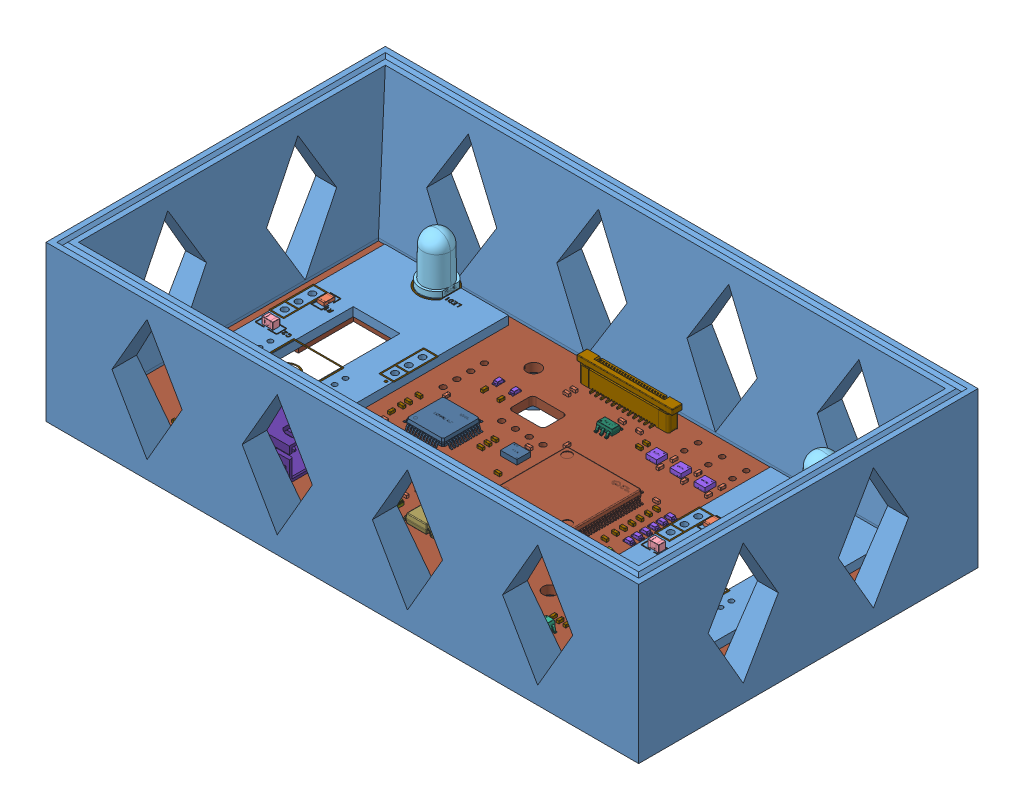
SolidWorks assembly main_v2, configuration Default. Lengths in mm.
Overall size (109.24 29.41 62.54).
295 component instances, 29 part files, 3 mates.
Components (placement in the parent):
- base_v2-1: base_v2 [Default] at origin size (109.24 28.6 62.54)
- 3D_Main_v2_2024-05-05.step-2: 3D_Main_v2_2024-05-05.step [Default] at (0 1.6 0) x (-1 0 0) z (0 1 0) size (99.21 49.97 14.78)
  - SGDi-C2.step-1: SGDi-C2.step [Default] at (-19.05 5.08 1.5862) x (0 -1 0) z (0 0 1) size (1 0.5 0.5)
    - C0402.step-1: C0402.step [Default] at origin size (1 0.5 0.5)
      - SOLID.step-1: SOLID.step [Default] at origin size (1 0.5 0.5)
  - SGDi-C6.step-1: SGDi-C6.step [Default] at (-17.78 -8.89 1.5862) size (1 0.5 0.5)
    - C0402.step-1: C0402.step [Default] at origin size (1 0.5 0.5)
      - SOLID.step-1: SOLID.step [Default] at origin size (1 0.5 0.5)
  - SGDi-C1.step-1: SGDi-C1.step [Default] at (-0.635 -9.525 1.5862) x (0 1 0) z (0 0 1) size (1 0.5 0.5)
    - C0402.step-1: C0402.step [Default] at origin size (1 0.5 0.5)
      - SOLID.step-1: SOLID.step [Default] at origin size (1 0.5 0.5)
  - SGDi-C14.step-1: SGDi-C14.step [Default] at (9.525 4.445 1.5862) size (1 0.5 0.5)
    - C0402.step-1: C0402.step [Default] at origin size (1 0.5 0.5)
      - SOLID.step-1: SOLID.step [Default] at origin size (1 0.5 0.5)
  - SGDi-C12.step-1: SGDi-C12.step [Default] at (20.32 3.175 1.5862) x (-1 0 0) z (0 0 1) size (1 0.5 0.5)
    - C0402.step-1: C0402.step [Default] at origin size (1 0.5 0.5)
      - SOLID.step-1: SOLID.step [Default] at origin size (1 0.5 0.5)
  - SGDi-C19.step-1: SGDi-C19.step [Default] at (18.415 -6.35 1.5862) x (0 1 0) z (0 0 1) size (1 0.5 0.5)
    - C0402.step-1: C0402.step [Default] at origin size (1 0.5 0.5)
      - SOLID.step-1: SOLID.step [Default] at origin size (1 0.5 0.5)
  - SGDi-C5.step-1: SGDi-C5.step [Default] at (-12.7 8.89 1.5862) x (-1 0 0) z (0 0 1) size (1 0.5 0.5)
    - C0402.step-1: C0402.step [Default] at origin size (1 0.5 0.5)
      - SOLID.step-1: SOLID.step [Default] at origin size (1 0.5 0.5)
  - SGDi-C7.step-1: SGDi-C7.step [Default] at (0 6.35 1.5862) x (-1 0 0) z (0 0 1) size (1 0.5 0.5)
    - C0402.step-1: C0402.step [Default] at origin size (1 0.5 0.5)
      - SOLID.step-1: SOLID.step [Default] at origin size (1 0.5 0.5)
  - SGDi-C3.step-1: SGDi-C3.step [Default] at (-11.557 11.43 1.5862) x (0 -1 0) z (0 0 1) size (1 0.5 0.5)
    - C0402.step-1: C0402.step [Default] at origin size (1 0.5 0.5)
      - SOLID.step-1: SOLID.step [Default] at origin size (1 0.5 0.5)
  - SGDi-C4.step-1: SGDi-C4.step [Default] at (-5.334 11.43 1.5862) x (0 1 0) z (0 0 1) size (1 0.5 0.5)
    - C0402.step-1: C0402.step [Default] at origin size (1 0.5 0.5)
      - SOLID.step-1: SOLID.step [Default] at origin size (1 0.5 0.5)
  - SGDi-C15.step-1: SGDi-C15.step [Default] at (11.43 6.35 1.5862) x (0 -1 0) z (0 0 1) size (1 0.5 0.5)
    - C0402.step-1: C0402.step [Default] at origin size (1 0.5 0.5)
      - SOLID.step-1: SOLID.step [Default] at origin size (1 0.5 0.5)
  - SGDi-C16.step-1: SGDi-C16.step [Default] at (17.78 6.35 1.5862) x (0 1 0) z (0 0 1) size (1 0.5 0.5)
    - C0402.step-1: C0402.step [Default] at origin size (1 0.5 0.5)
      - SOLID.step-1: SOLID.step [Default] at origin size (1 0.5 0.5)
  - SGDi-C23.step-1: SGDi-C23.step [Default] at (-5.08 16.256 1.5862) x (-1 0 0) z (0 0 1) size (1 0.5 0.5)
    - C0402.step-1: C0402.step [Default] at origin size (1 0.5 0.5)
      - SOLID.step-1: SOLID.step [Default] at origin size (1 0.5 0.5)
  - SGDi-C22.step-1: SGDi-C22.step [Default] at (5.715 11.43 1.5862) x (-1 0 0) z (0 0 1) size (1 0.5 0.5)
    - C0402.step-1: C0402.step [Default] at origin size (1 0.5 0.5)
      - SOLID.step-1: SOLID.step [Default] at origin size (1 0.5 0.5)
  - SGDi-C27.step-1: SGDi-C27.step [Default] at (6.35 19.05 1.5862) x (-1 0 0) z (0 0 1) size (1 0.5 0.5)
    - C0402.step-1: C0402.step [Default] at origin size (1 0.5 0.5)
      - SOLID.step-1: SOLID.step [Default] at origin size (1 0.5 0.5)
  - SGDi-C26.step-1: SGDi-C26.step [Default] at (6.35 13.335 1.5862) x (-1 0 0) z (0 0 1) size (1 0.5 0.5)
    - C0402.step-1: C0402.step [Default] at origin size (1 0.5 0.5)
      - SOLID.step-1: SOLID.step [Default] at origin size (1 0.5 0.5)
  - SGDi-C21.step-1: SGDi-C21.step [Default] at (2.54 11.43 1.5862) x (-1 0 0) z (0 0 1) size (1 0.5 0.5)
    - C0402.step-1: C0402.step [Default] at origin size (1 0.5 0.5)
      - SOLID.step-1: SOLID.step [Default] at origin size (1 0.5 0.5)
  - SGDi-C9.step-1: SGDi-C9.step [Default] at (7.62 -17.78 1.5862) size (1 0.5 0.5)
    - C0402.step-1: C0402.step [Default] at origin size (1 0.5 0.5)
      - SOLID.step-1: SOLID.step [Default] at origin size (1 0.5 0.5)
  - SGDi-C8.step-1: SGDi-C8.step [Default] at (7.62 -19.05 1.5862) size (1 0.5 0.5)
    - C0402.step-1: C0402.step [Default] at origin size (1 0.5 0.5)
      - SOLID.step-1: SOLID.step [Default] at origin size (1 0.5 0.5)
  - SGDi-C36.step-1: SGDi-C36.step [Default] at (36.0027 22.0445 1.5862) x (0 1 0) z (0 0 1) size (1 0.5 0.5)
    - C0402.step-1: C0402.step [Default] at origin size (1 0.5 0.5)
      - SOLID.step-1: SOLID.step [Default] at origin size (1 0.5 0.5)
  - SGDi-C11.step-1: SGDi-C11.step [Default] at (41.0827 18.2345 1.5862) x (0 -1 0) z (0 0 1) size (1 0.5 0.5)
    - C0402.step-1: C0402.step [Default] at origin size (1 0.5 0.5)
      - SOLID.step-1: SOLID.step [Default] at origin size (1 0.5 0.5)
  - SGDi-C32.step-1: SGDi-C32.step [Default] at (-42.5451 22.86 1.5862) x (0 1 0) z (0 0 1) size (1 0.5 0.5)
    - C0402.step-1: C0402.step [Default] at origin size (1 0.5 0.5)
      - SOLID.step-1: SOLID.step [Default] at origin size (1 0.5 0.5)
  - SGDi-C35.step-1: SGDi-C35.step [Default] at (-12.954 11.43 1.5862) x (0 -1 0) z (0 0 1) size (1 0.5 0.5)
    - C0402.step-1: C0402.step [Default] at origin size (1 0.5 0.5)
      - SOLID.step-1: SOLID.step [Default] at origin size (1 0.5 0.5)
  - SGDi-C24.step-1: SGDi-C24.step [Default] at (-21.59 -17.145 1.5862) x (0 1 0) z (0 0 1) size (1 0.5 0.5)
    - C0402.step-1: C0402.step [Default] at origin size (1 0.5 0.5)
      - SOLID.step-1: SOLID.step [Default] at origin size (1 0.5 0.5)
  - SGDi-C28.step-1: SGDi-C28.step [Default] at (-17.145 -17.145 1.5862) x (0 1 0) z (0 0 1) size (1 0.5 0.5)
    - C0402.step-1: C0402.step [Default] at origin size (1 0.5 0.5)
      - SOLID.step-1: SOLID.step [Default] at origin size (1 0.5 0.5)
  - SGDi-C30.step-1: SGDi-C30.step [Default] at (-12.7 -17.145 1.5862) x (0 1 0) z (0 0 1) size (1 0.5 0.5)
    - C0402.step-1: C0402.step [Default] at origin size (1 0.5 0.5)
      - SOLID.step-1: SOLID.step [Default] at origin size (1 0.5 0.5)
  - SGDi-C33.step-1: SGDi-C33.step [Default] at (2.54 -5.715 1.5862) size (1 0.5 0.5)
    - C0402.step-1: C0402.step [Default] at origin size (1 0.5 0.5)
      - SOLID.step-1: SOLID.step [Default] at origin size (1 0.5 0.5)
  - SGDi-C31.step-1: SGDi-C31.step [Default] at (-12.7 -14.605 1.5862) x (0 -1 0) z (0 0 1) size (1 0.5 0.5)
    - C0402.step-1: C0402.step [Default] at origin size (1 0.5 0.5)
      - SOLID.step-1: SOLID.step [Default] at origin size (1 0.5 0.5)
  - SGDi-C29.step-1: SGDi-C29.step [Default] at (-17.145 -14.605 1.5862) x (0 -1 0) z (0 0 1) size (1 0.5 0.5)
    - C0402.step-1: C0402.step [Default] at origin size (1 0.5 0.5)
      - SOLID.step-1: SOLID.step [Default] at origin size (1 0.5 0.5)
  - SGDi-C25.step-1: SGDi-C25.step [Default] at (-21.59 -14.605 1.5862) x (0 -1 0) z (0 0 1) size (1 0.5 0.5)
    - C0402.step-1: C0402.step [Default] at origin size (1 0.5 0.5)
      - SOLID.step-1: SOLID.step [Default] at origin size (1 0.5 0.5)
  - SGDi-C34.step-1: SGDi-C34.step [Default] at (-1.905 -18.415 1.5862) size (1 0.5 0.5)
    - C0402.step-1: C0402.step [Default] at origin size (1 0.5 0.5)
      - SOLID.step-1: SOLID.step [Default] at origin size (1 0.5 0.5)
  - SGDi-C37.step-1: SGDi-C37.step [Default] at (-5.08 -18.415 1.5862) x (-1 0 0) z (0 0 1) size (1 0.5 0.5)
    - C0402.step-1: C0402.step [Default] at origin size (1 0.5 0.5)
      - SOLID.step-1: SOLID.step [Default] at origin size (1 0.5 0.5)
  - SGDi-C10.step-1: SGDi-C10.step [Default] at (-6.35 8.89 1.5862) x (-1 0 0) z (0 0 1) size (1 0.5 0.5)
    - C0402.step-1: C0402.step [Default] at origin size (1 0.5 0.5)
      - SOLID.step-1: SOLID.step [Default] at origin size (1 0.5 0.5)
  - SGDi-C20.step-1: SGDi-C20.step [Default] at (2.54 9.525 1.5862) size (3.2 1.6 1.3)
    - C1206.step-1: C1206.step [Default] at origin size (3.2 1.6 1.3)
      - SOLID-0.step-1: SOLID-0.step [Default] at origin size (3.2 1.6 1.3)
  - SGDi-L1.step-1: SGDi-L1.step [Default] at (7.62 9.525 1.5862) x (-1 0 0) z (0 0 1) size (2 1.3 0.61)
    - L0805.step-1: L0805.step [Default] at origin size (2 1.3 0.61)
      - COMPOUND.step-1: COMPOUND.step [Default] at origin size (2 1.3 0.61)
  - SGDi-L2.step-1: SGDi-L2.step [Default] at (33.4627 18.7425 1.5862) x (0 1 0) z (0 0 1) size (3 3 1.52)
    - IND-SMD_L3.0-W3.0_FNR30XXS.step-1: IND-SMD_L3.0-W3.0_FNR30XXS.step [Default] at origin size (3 3 1.52)
      - SOLID-1.step-1: SOLID-1.step [Default] at origin size (3 3 1.52)
  - SGDi-LED10.step-1: SGDi-LED10.step [Default] at (-26.6701 15.24 1.5862) x (0 -1 0) z (0 0 1) size (2.02 1.26 1.01)
    - LED0805-R-RD.step-1: LED0805-R-RD.step [Default] at origin size (2.02 1.26 1.01)
      - COMPOUND-2.step-1: COMPOUND-2.step [Default] at origin size (2.02 1.26 1.01)
  - SGDi-LED11.step-1: SGDi-LED11.step [Default] at (-29.2101 15.24 1.5862) x (0 -1 0) z (0 0 1) size (2.02 1.26 1.01)
    - LED0805-R-RD.step-1: LED0805-R-RD.step [Default] at origin size (2.02 1.26 1.01)
      - COMPOUND-2.step-1: COMPOUND-2.step [Default] at origin size (2.02 1.26 1.01)
  - SGDi-LED1.step-1: SGDi-LED1.step [Default] at (-21.59 3.81 1.5862) x (0 -1 0) z (0 0 1) size (1.62 0.81 0.81)
    - LED0603-R-RD_WHITE.step-1: LED0603-R-RD_WHITE.step [Default] at origin size (1.62 0.81 0.81)
      - COMPOUND-3.step-1: COMPOUND-3.step [Default] at origin size (1.62 0.81 0.81)
  - SGDi-LED6.step-1: SGDi-LED6.step [Default] at (-21.59 -3.048 1.5862) size (1.62 0.82 0.56)
    - LED0603-RD-YELLOW.step-1: LED0603-RD-YELLOW.step [Default] at origin size (1.62 0.82 0.56)
      - COMPOUND-4.step-1: COMPOUND-4.step [Default] at origin size (1.62 0.82 0.56)
  - SGDi-LED7.step-1: SGDi-LED7.step [Default] at (-21.59 -4.572 1.5862) size (1.62 0.82 0.56)
    - LED0603-RD-YELLOW.step-1: LED0603-RD-YELLOW.step [Default] at origin size (1.62 0.82 0.56)
      - COMPOUND-4.step-1: COMPOUND-4.step [Default] at origin size (1.62 0.82 0.56)
  - SGDi-LED8.step-1: SGDi-LED8.step [Default] at (-21.59 -6.096 1.5862) size (1.62 0.82 0.56)
    - LED0603-RD-YELLOW.step-1: LED0603-RD-YELLOW.step [Default] at origin size (1.62 0.82 0.56)
      - COMPOUND-4.step-1: COMPOUND-4.step [Default] at origin size (1.62 0.82 0.56)
  - SGDi-LED9.step-1: SGDi-LED9.step [Default] at (-21.59 -7.62 1.5862) size (1.62 0.82 0.56)
    - LED0603-RD-YELLOW.step-1: LED0603-RD-YELLOW.step [Default] at origin size (1.62 0.82 0.56)
      - COMPOUND-4.step-1: COMPOUND-4.step [Default] at origin size (1.62 0.82 0.56)
  - SGDi-LED3.step-1: SGDi-LED3.step [Default] at (12.827 -13.335 1.5862) x (0 1 0) z (0 0 1) size (1.62 0.82 0.56)
    - LED0603-RD-YELLOW.step-1: LED0603-RD-YELLOW.step [Default] at origin size (1.62 0.82 0.56)
      - COMPOUND-4.step-1: COMPOUND-4.step [Default] at origin size (1.62 0.82 0.56)
  - SGDi-LED2.step-1: SGDi-LED2.step [Default] at (15.875 -13.335 1.5862) x (0 1 0) z (0 0 1) size (1.62 0.82 0.56)
    - LED0603-RD-YELLOW.step-1: LED0603-RD-YELLOW.step [Default] at origin size (1.62 0.82 0.56)
      - COMPOUND-4.step-1: COMPOUND-4.step [Default] at origin size (1.62 0.82 0.56)
  - SGDi-LED4.step-1: SGDi-LED4.step [Default] at (-21.59 0 1.5862) size (1.62 0.82 0.56)
    - LED0603-RD-YELLOW.step-1: LED0603-RD-YELLOW.step [Default] at origin size (1.62 0.82 0.56)
      - COMPOUND-4.step-1: COMPOUND-4.step [Default] at origin size (1.62 0.82 0.56)
  - SGDi-LED5.step-1: SGDi-LED5.step [Default] at (-21.59 -1.524 1.5862) size (1.62 0.82 0.56)
    - LED0603-RD-YELLOW.step-1: LED0603-RD-YELLOW.step [Default] at origin size (1.62 0.82 0.56)
      - COMPOUND-4.step-1: COMPOUND-4.step [Default] at origin size (1.62 0.82 0.56)
  - SGDi-R2.step-1: SGDi-R2.step [Default] at (-10.16 8.89 1.5862) size (1 0.5 0.5)
    - R0402.step-1: R0402.step [Default] at origin size (1 0.5 0.5)
      - SOLID-5.step-1: SOLID-5.step [Default] at origin size (1 0.5 0.5)
  - SGDi-R6.step-1: SGDi-R6.step [Default] at (9.525 5.715 1.5862) size (1 0.5 0.5)
    - R0402.step-1: R0402.step [Default] at origin size (1 0.5 0.5)
      - SOLID-5.step-1: SOLID-5.step [Default] at origin size (1 0.5 0.5)
  - SGDi-R7.step-1: SGDi-R7.step [Default] at (20.955 -0.635 1.5862) size (1 0.5 0.5)
    - R0402.step-1: R0402.step [Default] at origin size (1 0.5 0.5)
      - SOLID-5.step-1: SOLID-5.step [Default] at origin size (1 0.5 0.5)
  - SGDi-R16.step-1: SGDi-R16.step [Default] at (6.985 -1.27 1.5862) x (-1 0 0) z (0 0 1) size (1 0.5 0.5)
    - R0402.step-1: R0402.step [Default] at origin size (1 0.5 0.5)
      - SOLID-5.step-1: SOLID-5.step [Default] at origin size (1 0.5 0.5)
  - SGDi-R17.step-1: SGDi-R17.step [Default] at (6.985 -3.81 1.5862) x (-1 0 0) z (0 0 1) size (1 0.5 0.5)
    - R0402.step-1: R0402.step [Default] at origin size (1 0.5 0.5)
      - SOLID-5.step-1: SOLID-5.step [Default] at origin size (1 0.5 0.5)
  - SGDi-R18.step-1: SGDi-R18.step [Default] at (6.985 -2.54 1.5862) x (-1 0 0) z (0 0 1) size (1 0.5 0.5)
    - R0402.step-1: R0402.step [Default] at origin size (1 0.5 0.5)
      - SOLID-5.step-1: SOLID-5.step [Default] at origin size (1 0.5 0.5)
  - SGDi-R19.step-1: SGDi-R19.step [Default] at (20.955 1.27 1.5862) x (0 1 0) z (0 0 1) size (1 0.5 0.5)
    - R0402.step-1: R0402.step [Default] at origin size (1 0.5 0.5)
      - SOLID-5.step-1: SOLID-5.step [Default] at origin size (1 0.5 0.5)
  - SGDi-R20.step-1: SGDi-R20.step [Default] at (20.955 -1.905 1.5862) size (1 0.5 0.5)
    - R0402.step-1: R0402.step [Default] at origin size (1 0.5 0.5)
      - SOLID-5.step-1: SOLID-5.step [Default] at origin size (1 0.5 0.5)
  - SGDi-R21.step-1: SGDi-R21.step [Default] at (20.955 -3.81 1.5862) x (-1 0 0) z (0 0 1) size (1 0.5 0.5)
    - R0402.step-1: R0402.step [Default] at origin size (1 0.5 0.5)
      - SOLID-5.step-1: SOLID-5.step [Default] at origin size (1 0.5 0.5)
  - SGDi-R22.step-1: SGDi-R22.step [Default] at (39.1777 22.8065 1.5862) x (-1 0 0) z (0 0 1) size (1 0.5 0.5)
    - R0402.step-1: R0402.step [Default] at origin size (1 0.5 0.5)
      - SOLID-5.step-1: SOLID-5.step [Default] at origin size (1 0.5 0.5)
  - SGDi-R26.step-1: SGDi-R26.step [Default] at (39.1777 20.7745 1.5862) x (-1 0 0) z (0 0 1) size (1 0.5 0.5)
    - R0402.step-1: R0402.step [Default] at origin size (1 0.5 0.5)
      - SOLID-5.step-1: SOLID-5.step [Default] at origin size (1 0.5 0.5)
  - SGDi-R24.step-1: SGDi-R24.step [Default] at (39.1777 21.7905 1.5862) size (1 0.5 0.5)
    - R0402.step-1: R0402.step [Default] at origin size (1 0.5 0.5)
      - SOLID-5.step-1: SOLID-5.step [Default] at origin size (1 0.5 0.5)
  - SGDi-R27.step-1: SGDi-R27.step [Default] at (-26.6701 19.05 1.5862) x (0 -1 0) z (0 0 1) size (1 0.5 0.5)
    - R0402.step-1: R0402.step [Default] at origin size (1 0.5 0.5)
      - SOLID-5.step-1: SOLID-5.step [Default] at origin size (1 0.5 0.5)
  - SGDi-R29.step-1: SGDi-R29.step [Default] at (-27.9401 19.05 1.5862) x (0 -1 0) z (0 0 1) size (1 0.5 0.5)
    - R0402.step-1: R0402.step [Default] at origin size (1 0.5 0.5)
      - SOLID-5.step-1: SOLID-5.step [Default] at origin size (1 0.5 0.5)
  - SGDi-R28.step-1: SGDi-R28.step [Default] at (-29.2101 19.05 1.5862) x (0 -1 0) z (0 0 1) size (1 0.5 0.5)
    - R0402.step-1: R0402.step [Default] at origin size (1 0.5 0.5)
      - SOLID-5.step-1: SOLID-5.step [Default] at origin size (1 0.5 0.5)
  - SGDi-R23.step-1: SGDi-R23.step [Default] at (-14.986 11.43 1.5862) x (0 1 0) z (0 0 1) size (1 0.5 0.5)
    - R0402.step-1: R0402.step [Default] at origin size (1 0.5 0.5)
      - SOLID-5.step-1: SOLID-5.step [Default] at origin size (1 0.5 0.5)
  - SGDi-R25.step-1: SGDi-R25.step [Default] at (-13.97 11.43 1.5862) x (0 -1 0) z (0 0 1) size (1 0.5 0.5)
    - R0402.step-1: R0402.step [Default] at origin size (1 0.5 0.5)
      - SOLID-5.step-1: SOLID-5.step [Default] at origin size (1 0.5 0.5)
  - SGDi-R8.step-1: SGDi-R8.step [Default] at (-19.05 0 1.5862) size (1 0.5 0.5)
    - R0402.step-1: R0402.step [Default] at origin size (1 0.5 0.5)
      - SOLID-5.step-1: SOLID-5.step [Default] at origin size (1 0.5 0.5)
  - SGDi-R9.step-1: SGDi-R9.step [Default] at (-19.05 -1.524 1.5862) size (1 0.5 0.5)
    - R0402.step-1: R0402.step [Default] at origin size (1 0.5 0.5)
      - SOLID-5.step-1: SOLID-5.step [Default] at origin size (1 0.5 0.5)
  - SGDi-R10.step-1: SGDi-R10.step [Default] at (-19.05 -3.048 1.5862) size (1 0.5 0.5)
    - R0402.step-1: R0402.step [Default] at origin size (1 0.5 0.5)
      - SOLID-5.step-1: SOLID-5.step [Default] at origin size (1 0.5 0.5)
  - SGDi-R11.step-1: SGDi-R11.step [Default] at (-19.05 -4.572 1.5862) size (1 0.5 0.5)
    - R0402.step-1: R0402.step [Default] at origin size (1 0.5 0.5)
      - SOLID-5.step-1: SOLID-5.step [Default] at origin size (1 0.5 0.5)
  - SGDi-R12.step-1: SGDi-R12.step [Default] at (-19.05 -6.096 1.5862) size (1 0.5 0.5)
    - R0402.step-1: R0402.step [Default] at origin size (1 0.5 0.5)
      - SOLID-5.step-1: SOLID-5.step [Default] at origin size (1 0.5 0.5)
  - SGDi-R13.step-1: SGDi-R13.step [Default] at (-19.05 -7.62 1.5862) size (1 0.5 0.5)
    - R0402.step-1: R0402.step [Default] at origin size (1 0.5 0.5)
      - SOLID-5.step-1: SOLID-5.step [Default] at origin size (1 0.5 0.5)
  - SGDi-R5.step-1: SGDi-R5.step [Default] at (-19.05 1.905 1.5862) size (1 0.5 0.5)
    - R0402.step-1: R0402.step [Default] at origin size (1 0.5 0.5)
      - SOLID-5.step-1: SOLID-5.step [Default] at origin size (1 0.5 0.5)
  - SGDi-R3.step-1: SGDi-R3.step [Default] at (-7.62 -15.875 1.5862) x (-1 0 0) z (0 0 1) size (1 0.5 0.5)
    - R0402.step-1: R0402.step [Default] at origin size (1 0.5 0.5)
      - SOLID-5.step-1: SOLID-5.step [Default] at origin size (1 0.5 0.5)
  - SGDi-R4.step-1: SGDi-R4.step [Default] at (-7.62 -17.145 1.5862) x (-1 0 0) z (0 0 1) size (1 0.5 0.5)
    - R0402.step-1: R0402.step [Default] at origin size (1 0.5 0.5)
      - SOLID-5.step-1: SOLID-5.step [Default] at origin size (1 0.5 0.5)
  - SGDi-R14.step-1: SGDi-R14.step [Default] at (12.827 -10.795 1.5862) x (0 1 0) z (0 0 1) size (1 0.5 0.5)
    - R0402.step-1: R0402.step [Default] at origin size (1 0.5 0.5)
      - SOLID-5.step-1: SOLID-5.step [Default] at origin size (1 0.5 0.5)
  - SGDi-R15.step-1: SGDi-R15.step [Default] at (15.875 -10.795 1.5862) x (0 1 0) z (0 0 1) size (1 0.5 0.5)
    - R0402.step-1: R0402.step [Default] at origin size (1 0.5 0.5)
      - SOLID-5.step-1: SOLID-5.step [Default] at origin size (1 0.5 0.5)
  - SGDi-R1.step-1: SGDi-R1.step [Default] at (1.27 1.27 1.5862) size (1 0.5 0.5)
    - R0402.step-1: R0402.step [Default] at origin size (1 0.5 0.5)
      - SOLID-5.step-1: SOLID-5.step [Default] at origin size (1 0.5 0.5)
  - SGDi-U10.step-1: SGDi-U10.step [Default] at (2.54 -3.175 1.5862) size (3 2.5 0.92)
    - LGA-14_L3.0-W2.5-P0.50-TL.step-1: LGA-14_L3.0-W2.5-P0.50-TL.step [Default] at origin size (3 2.5 0.92)
      - COMPOUND-6.step-1: COMPOUND-6.step [Default] at origin size (3 2.5 0.92)
  - SGDi-U1.step-1: SGDi-U1.step [Default] at (-8.89 -1.27 1.5862) x (-1 0 0) z (0 0 1) size (16 16 1.5)
    - LQFP-100_L14.0-W14.0-P0.50-LS16.0-BL.step-1: LQFP-100_L14.0-W14.0-P0.50-LS16.0-BL.step [Default] at origin size (16 16 1.5)
      - SOLID-7.step-1: SOLID-7.step [Default] at origin size (16 16 1.5)
  - SGDi-U5.step-1: SGDi-U5.step [Default] at (0 15.24 1.5862) x (0 1 0) z (0 0 1) size (5 6 1.8)
    - SSOP-10_L5.0-W3.9-P1.00-LS6.0-BL-EP.step-1: SSOP-10_L5.0-W3.9-P1.00-LS6.0-BL-EP.step [Default] at origin size (5 6 1.8)
      - COMPOUND-8.step-1: COMPOUND-8.step [Default] at origin size (5 6 1.8)
  - SGDi-U9.step-1: SGDi-U9.step [Default] at (-39.3701 19.685 1.5862) size (4.9 6 1.5)
    - SOP-8_L4.9-W3.9-P1.27-LS6.0-BL.step-1: SOP-8_L4.9-W3.9-P1.27-LS6.0-BL.step [Default] at origin size (4.9 6 1.5)
      - COMPOUND-9.step-1: COMPOUND-9.step [Default] at origin size (4.9 6 1.5)
  - SGDi-U12.step-1: SGDi-U12.step [Default] at (37.9077 18.2345 1.5862) x (-1 0 0) z (0 0 1) size (2.89 2.78 1.2)
    - SOT-23-5_L3.0-W1.7-P0.95-LS2.8-BR.step-1: SOT-23-5_L3.0-W1.7-P0.95-LS2.8-BR.step [Default] at origin size (2.89 2.78 1.2)
      - COMPOUND-10.step-1: COMPOUND-10.step [Default] at origin size (2.89 2.78 1.2)
  - SGDi-U11.step-1: SGDi-U11.step [Default] at (-1.905 -15.875 1.5862) x (-1 0 0) z (0 0 1) size (2.9 3.01 1.25)
    - SOT-23-5_L3.0-W1.7-P0.95-LS2.8-BL.step-1: SOT-23-5_L3.0-W1.7-P0.95-LS2.8-BL.step [Default] at origin size (2.9 3.01 1.25)
      - COMPOUND-11.step-1: COMPOUND-11.step [Default] at origin size (2.9 3.01 1.25)
  - SGDi-X3.step-1: SGDi-X3.step [Default] at (6.35 16.256 1.5862) x (0 1 0) z (0 0 1) size (3.2 2.5 0.81)
    - CRYSTAL-SMD_4P-L3.2-W2.5-BL.step-1: CRYSTAL-SMD_4P-L3.2-W2.5-BL.step [Default] at origin size (3.2 2.5 0.81)
      - SOLID-12.step-1: SOLID-12.step [Default] at origin size (3.2 2.5 0.81)
  - SGDi-CN1.step-1: SGDi-CN1.step [Default] at (24.13 18.415 1.5862) x (0 -1 0) z (0 0 1) size (10 10.5 6.2)
    - CONN-SMD_2P-P2.54_MEGASTAR_ZX-XH2.54-2PWT.step-1: CONN-SMD_2P-P2.54_MEGASTAR_ZX-XH2.54-2PWT.step [Default] at origin size (10 10.5 6.2)
      - SOLID-13.step-1: SOLID-13.step [Default] at origin size (10 10.5 6.2)
  - SGDi-U4.step-1: SGDi-U4.step [Default] at (35.5601 5.08 1.5862) size (23.12 37.59 14.78)
    - PAW3205DB+LED.step-1: PAW3205DB+LED.step [Default] at origin size (23.12 37.59 14.78)
      - COMPOUND-14.step-1: COMPOUND-14.step [Default] at origin size (23.12 37.31 0.09)
      - SOLID-15.step-1: SOLID-15.step [Default] at origin size (22.77 36.16 1.6)
      - COMPOUND-16.step-1: COMPOUND-16.step [Default] at origin size (1.3 2 0.61)
      - SOLID-17.step-1: SOLID-17.step [Default] at origin size (2 1.3 1.3)
      - SOLID-18.step-1: SOLID-18.step [Default] at origin size (2 1.3 1.3)
      - SOLID-19.step-1: SOLID-19.step [Default] at origin size (5.65 6.08 14.78)
  - SGDi-U2.step-1: SGDi-U2.step [Default] at (-35.5601 5.08 1.5862) size (23.12 37.59 14.78)
    - PAW3205DB+LED.step-1: PAW3205DB+LED.step [Default] at origin size (23.12 37.59 14.78)
      - COMPOUND-14.step-1: COMPOUND-14.step [Default] at origin size (23.12 37.31 0.09)
      - SOLID-15.step-1: SOLID-15.step [Default] at origin size (22.77 36.16 1.6)
      - COMPOUND-16.step-1: COMPOUND-16.step [Default] at origin size (1.3 2 0.61)
      - SOLID-17.step-1: SOLID-17.step [Default] at origin size (2 1.3 1.3)
      - SOLID-18.step-1: SOLID-18.step [Default] at origin size (2 1.3 1.3)
      - SOLID-19.step-1: SOLID-19.step [Default] at origin size (5.65 6.08 14.78)
  - SGDi-U13.step-1: SGDi-U13.step [Default] at (-27.9401 22.225 1.5862) size (2.81 2.9 1.65)
    - SOT-23-6_L2.9-W1.6-P0.95-LS2.8-BR.step-1: SOT-23-6_L2.9-W1.6-P0.95-LS2.8-BR.step [Default] at origin size (2.81 2.9 1.65)
      - COMPOUND-20.step-1: COMPOUND-20.step [Default] at origin size (2.81 2.9 1.65)
  - SGDi-X2.step-1: SGDi-X2.step [Default] at (14.732 6.35 1.5862) x (-1 0 0) z (0 0 1) size (3.2 2.5 0.81)
    - OSC-SMD_4P-L3.2-W2.5-BL.step-1: OSC-SMD_4P-L3.2-W2.5-BL.step [Default] at origin size (3.2 2.5 0.81)
      - SOLID-21.step-1: SOLID-21.step [Default] at origin size (3.2 2.5 0.81)
  - SGDi-X1.step-1: SGDi-X1.step [Default] at (-8.382 11.43 1.5862) x (-1 0 0) z (0 0 1) size (3.2 2.5 0.81)
    - OSC-SMD_4P-L3.2-W2.5-BL.step-1: OSC-SMD_4P-L3.2-W2.5-BL.step [Default] at origin size (3.2 2.5 0.81)
      - SOLID-21.step-1: SOLID-21.step [Default] at origin size (3.2 2.5 0.81)
  - SGDi-U7.step-1: SGDi-U7.step [Default] at (-15.24 -15.875 1.5862) x (0 1 0) z (0 0 1) size (2.02 2 0.81)
    - WSON-8_L2.0-W2.0-P0.50-TL-EP.step-1: WSON-8_L2.0-W2.0-P0.50-TL-EP.step [Default] at origin size (2.02 2 0.81)
      - COMPOUND-22.step-1: COMPOUND-22.step [Default] at origin size (2.02 2 0.81)
  - SGDi-U8.step-1: SGDi-U8.step [Default] at (-10.795 -15.875 1.5862) x (0 1 0) z (0 0 1) size (2.02 2 0.81)
    - WSON-8_L2.0-W2.0-P0.50-TL-EP.step-1: WSON-8_L2.0-W2.0-P0.50-TL-EP.step [Default] at origin size (2.02 2 0.81)
      - COMPOUND-22.step-1: COMPOUND-22.step [Default] at origin size (2.02 2 0.81)
  - SGDi-U6.step-1: SGDi-U6.step [Default] at (-19.685 -15.875 1.5862) x (0 1 0) z (0 0 1) size (2.02 2 0.81)
    - WSON-8_L2.0-W2.0-P0.50-TL-EP.step-1: WSON-8_L2.0-W2.0-P0.50-TL-EP.step [Default] at origin size (2.02 2 0.81)
      - COMPOUND-22.step-1: COMPOUND-22.step [Default] at origin size (2.02 2 0.81)
  - SGDi-FPC2.step-1: SGDi-FPC2.step [Default] at (0 -21.59 1.5862) size (17.6 3 4.4)
    - CONN-SMD-24_AFC11-S24ICA-00.step-1: CONN-SMD-24_AFC11-S24ICA-00.step [Default] at origin size (17.6 3 4.4)
      - COMPOUND-23.step-1: COMPOUND-23.step [Default] at origin size (17.6 3 4.4)
  - SGDi-U3.step-1: SGDi-U3.step [Default] at (13.97 -1.27 1.5862) x (-1 0 0) z (0 0 1) size (9 9 1.45)
    - LQFP-48_L7.0-W7.0-P0.50-LS9.0-BL.step-1: LQFP-48_L7.0-W7.0-P0.50-LS9.0-BL.step [Default] at origin size (9 9 1.45)
      - COMPOUND-24.step-1: COMPOUND-24.step [Default] at origin size (9 9 1.45)
  - Board.step-1: Board.step [Default] at origin size (99.21 49.97 1.59)
Mates (geometry in assembly coordinates):
- Coincident4: coincident anti-aligned: plane of base_v2-1 through (0 1.6 0) normal (0 1 0); plane of 3D_Main_v2_2024-05-05.step-2/Board.step-1 through (0 1.6 0) normal (0 -1 0)
- Concentric1: concentric anti-aligned: cylinder of base_v2-1 through (22 18.5857 15) axis (0 -1 0) radius 5; cylinder of 3D_Main_v2_2024-05-05.step-2/Board.step-1 through (22.0001 1.6 15.0001) axis (0 1 0) radius 1.3
- Concentric2: concentric anti-aligned: cylinder of base_v2-1 through (-15 18.5857 -19) axis (0 -1 0) radius 5; cylinder of 3D_Main_v2_2024-05-05.step-2/Board.step-1 through (-15 1.6 -19) axis (0 1 0) radius 1.3
